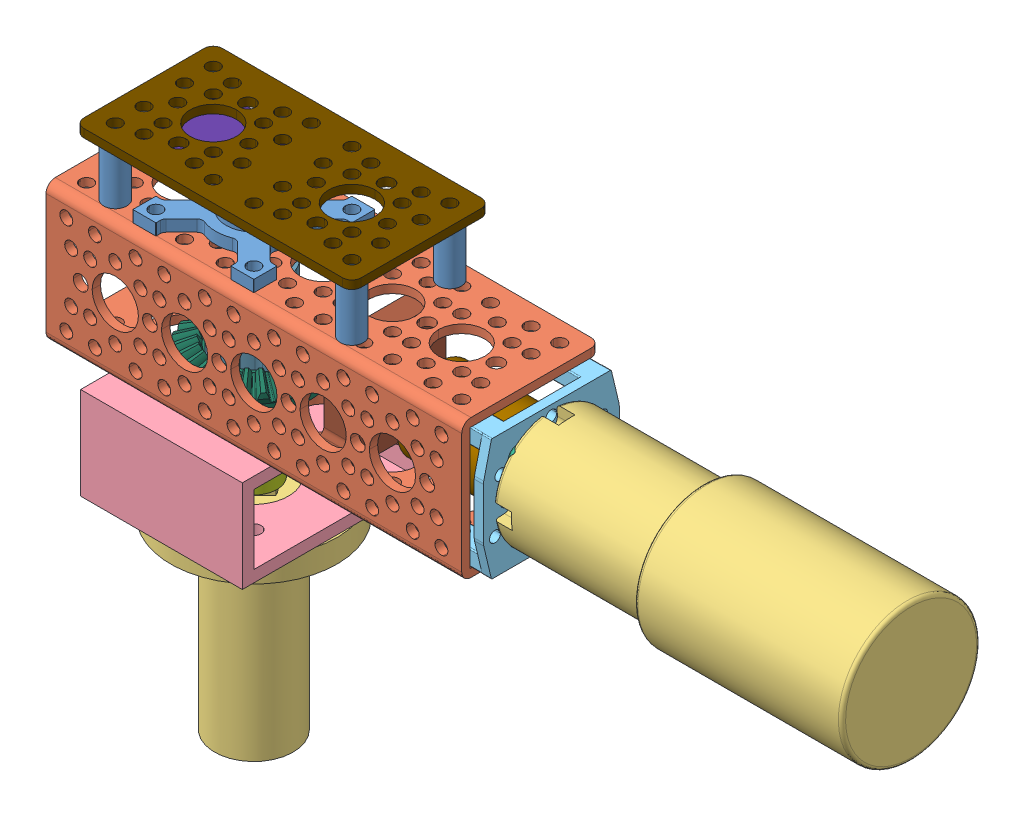
SolidWorks assembly LOX Valve, configuration Default. Lengths in mm.
Overall size (226.04 159.27 90.41).
38 component instances, 22 part files, 46 mates.
Components (placement in the parent):
- 535110 assembly - Pillow-1: 535110 assembly - Pillow [Default] at (31.7683 60.9694 -25.573) x (-0.000062 0 1) z (-1 0 -0.000062) size (33.27 5.08 33.27)
  - 535110 assembly - Pillow.STEP-1: 535110 assembly - Pillow.STEP [Default] at origin size (33.27 5.08 33.27)
    - 535110.STEP-1: 535110.STEP [Default] at (6.6273 15.2478 28.3097) size (33.27 5.08 33.27)
    - 535020.STEP-1: 535020.STEP [Default] at (6.6273 17.9338 28.3097) size (12.7 4.76 12.7)
- Motor_12VDC_638263-1: Motor_12VDC_638263 [Default] at (82.2478 57.1672 -18.9431) x (0 -0.998953 -0.04574) z (0 0.04574 -0.998953) size (38 101.9 38)
- Motor_12VDC_638263_shaft-1: Motor_12VDC_638263_shaft [Default] at (82.2478 57.1672 -18.9431) x (0 -0.998953 -0.04574) z (0 0.04574 -0.998953) size (6 16.2 6)
- 555188 assembly.STEP-1: 555188 assembly.STEP [Default] at (87.0217 63.6465 -16.3279) x (0 1 0) z (0 0 1) size (33.4 16.56 37.36)
  - 555188.STEP-1: 555188.STEP [Default] at (-6.4793 1.7739 -2.6152) size (33.4 14.22 37.36)
  - 555188 screw_92005A116.STEP-1: 555188 screw_92005A116.STEP [Default] at (-15.6717 7.7739 6.5772) x (1 0 0) z (0 -1 0) size (6 6 8.35)
  - 555188 screw_92005A116.STEP-2: 555188 screw_92005A116.STEP [Default] at (2.7131 7.7739 6.5772) x (0 0 -1) z (0 -1 0) size (6 6 8.35)
  - 555188 screw_92005A116.STEP-3: 555188 screw_92005A116.STEP [Default] at (2.7131 7.7739 -11.8076) x (-1 0 0) z (0 -1 0) size (6 6 8.35)
  - 555188 screw_92005A116.STEP-4: 555188 screw_92005A116.STEP [Default] at (-15.6717 7.7739 -11.8076) x (0 0 1) z (0 -1 0) size (6 6 8.35)
- 625182 assembly-2: 625182 assembly [Default] at (-84.2332 5.7417 -25.2481) x (-0.912422 0 -0.40925) z (0.40925 0 -0.912422) size (12.69 19.05 12.7)
- D-shaft-2.25in-1: D-shaft-2.25in [Default] at (3.4582 25.9129 -18.9475) x (0.746779 0 -0.665072) z (0.665072 0 0.746779) size (6.35 57.15 7.62)
- 625100 assembly.STEP-1: 625100 assembly.STEP [Default] at (87.2312 83.6106 5.6212) x (0 0.726073 0.687617) z (-1 0 0) size (50.01 22.2 75.17)
  - 625100.STEP-1: 625100.STEP [Default] at (-36.0907 -0.3474 4.9835) size (22.23 22.2 28.57)
  - 632112_90128A121.STEP-1: 632112_90128A121.STEP [Default] at (-1.3244 -7.8756 30.0025) x (0 0 -1) z (1 0 0) size (5.61 5.61 14.62)
  - 632112_90128A121.STEP-2: 632112_90128A121.STEP [Default] at (-1.3244 -7.8756 23.5255) x (0 0 -1) z (1 0 0) size (5.61 5.61 14.62)
  - 632112_90128A121.STEP-3: 632112_90128A121.STEP [Default] at (-1.3244 -7.8756 15.0165) x (0 0 -1) z (1 0 0) size (5.61 5.61 14.62)
  - 632112_90128A121.STEP-4: 632112_90128A121.STEP [Default] at (-1.3244 -7.8756 8.5395) x (0 0 -1) z (1 0 0) size (5.61 5.61 14.62)
- 535130 assembly.STEP-1: 535130 assembly.STEP [Default] at (22.1195 49.5488 9.4486) x (0 1 0) z (0 0 -1) size (33.54 6.36 33.02)
  - 535130.STEP-1: 535130.STEP [Default] at (7.6184 14.2154 28.3917) size (33.54 6.36 33.02)
  - 535020.STEP-1: 535020.STEP [Default] at (7.6184 18.1715 28.3917) size (12.7 4.76 12.7)
- 615458 assembly.STEP-1: 615458 assembly.STEP [Default] at (-39.0871 82.1155 -34.6634) x (-1 0 0) z (0 -0.723056 0.690789) size (72.51 19.24 80.12)
  - 615458.STEP-1: 615458.STEP [Default] at (-61.4441 5.8673 28.8984) size (15.1 19.24 19.22)
  - 632110_90128A121.STEP-1: 632110_90128A121.STEP [Default] at (-66.148 1.368 -6.0266) x (-0.354662 -0.934995 0) z (0 0 -1) size (5.61 5.61 13.03)
- 545309.step-1: 545309.step [Default] at (3.4582 53.843 -18.9475) x (0.920966 0 -0.389644) z (0 -1 0) size (17.78 17.76 20.07)
- 615460.step-1: 615460.step [Default] at (3.4582 43.8848 -18.9475) x (0 1 0) z (-0.857986 0 0.513673) size (8.04 33.75 33.87)
- D-shaft-2in-3: D-shaft-2in [Default] at (16.4618 57.1672 -18.9431) x (0 -0.983443 -0.181218) z (0 -0.181218 0.983443) size (5.71 50.8 6.35)
- AS5047 eval board-1: AS5047 eval board [Default] at (-3.2261 90.8222 -18.8412) x (1 0 0.000062) z (-0.000062 0 1) size (28 1.27 22)
- 585422.step-1: 585422.step [Default] at (11.3489 92.0922 -18.947) x (1 0 0.000062) z (-0.000062 0 1) size (76.2 2.29 38.1)
- .625in standoff-1: .625in standoff [Default] at (43.8685 92.0922 -5.4746) x (-0.12043 0 -0.992722) z (-0.992722 0 0.12043) size (6.35 15.88 6.35)
- .625in standoff-2: .625in standoff [Default] at (43.8701 76.2172 -32.4154) x (0.998481 0 -0.055099) z (0.055099 0 0.998481) size (6.35 15.88 6.35)
- 585444-2: 585444 [Default] at (-34.643 76.2172 0.1002) x (0 -1 0) z (1 0 0.000062) size (38.1 38.1 114.3)
- LOX Valve Body-1: LOX Valve Body [Default] at (3.4582 6.3672 -18.9475) x (-0.707063 0 -0.70715) z (0.70715 0 -0.707063) size (45.72 66.04 45.72)
- Lox-bracket-2-2: Lox-bracket-2 [Default] at (3.4582 12.7172 -18.9475) x (-0.000062 0 1) z (-1 0 -0.000062) size (50.8 25.4 44.45)
- .625in standoff-3: .625in standoff [Default] at (-21.1706 92.0922 -32.4194) x (-0.12043 0 -0.992722) z (-0.992722 0 0.12043) size (6.35 15.88 6.35)
- .625in standoff-4: .625in standoff [Default] at (-21.1723 92.0922 -5.4786) x (-0.119905 0 -0.992785) z (-0.992785 0 0.119905) size (6.35 15.88 6.35)
Mates (geometry in assembly coordinates):
- Concentric8: concentric: circle of Motor_12VDC_638263-1; circle of Motor_12VDC_638263_shaft-1
- Coincident8: coincident: plane of Motor_12VDC_638263-1 through (82.2478 57.1672 -18.9431) normal (-1 0 0); plane of Motor_12VDC_638263_shaft-1 through (82.2478 57.1672 -18.9431) normal (1 0 0)
- Concentric10: concentric: cylinder of Motor_12VDC_638263-1 through (127.0478 57.1672 -18.9431) axis (-1 0 0) radius 16; circle of 555188 assembly.STEP-1/555188.STEP-1
- Distance4: distance = 2.54 mm: plane of Motor_12VDC_638263-1 through (85.2478 57.1672 -18.9431) normal (-1 0 0); plane of 555188 assembly.STEP-1/555188.STEP-1 through (82.7078 57.1672 -18.9431) normal (-1 0 0)
- Coincident16: coincident: circle of 625182 assembly-2; plane of D-shaft-2.25in-1 through (3.4582 25.9129 -18.9475) normal (0 -1 0)
- Concentric13: concentric: cylinder of 625182 assembly-2 through (3.4582 34.9422 -18.9475) axis (0 1 0) radius 3.175; cylinder of D-shaft-2.25in-1 through (3.4582 83.0629 -18.9475) axis (0 -1 0) radius 3.175
- Concentric20: concentric: cylinder of Motor_12VDC_638263_shaft-1 through (66.0478 57.1672 -18.9431) axis (1 0 0) radius 3; cylinder of 625100 assembly.STEP-1/625100.STEP-1 through (67.9603 57.1672 -18.9431) axis (-1 0 0) radius 3
- Coincident25: coincident: plane of Motor_12VDC_638263-1 through (82.2478 57.1672 -18.9431) normal (-1 0 0); plane of 625100 assembly.STEP-1/625100.STEP-1 through (82.2478 57.1672 -18.9431) normal (1 0 0)
- Concentric21: concentric: cylinder of D-shaft-2.25in-1 through (3.4582 83.0629 -18.9475) axis (0 -1 0) radius 3.175; cylinder of 545309.step-1 through (3.4582 47.493 -18.9475) axis (0 1 0) radius 3.175
- Coincident26: coincident: cylinder of D-shaft-2.25in-1 through (3.4582 83.0629 -18.9475) axis (0 -1 0) radius 3.175; circle of 615460.step-1
- Coincident28: coincident: plane of 545309.step-1 through (3.4582 47.493 -18.9475) normal (0 -1 0); plane of 615460.step-1 through (3.4582 47.493 -18.9475) normal (0 1 0)
- Concentric22: concentric: cylinder of 625100 assembly.STEP-1/625100.STEP-1 through (67.9603 57.1672 -18.9431) axis (-1 0 0) radius 3; cylinder of 615458 assembly.STEP-1/615458.STEP-1 through (15.484 57.1672 -18.9431) axis (1 0 0) radius 3
- Concentric32: concentric: cylinder of 625100 assembly.STEP-1/625100.STEP-1 through (67.9603 57.1672 -18.9431) axis (-1 0 0) radius 3; cylinder of D-shaft-2in-3 through (67.2618 57.1672 -18.9431) axis (-1 0 0) radius 3.175
- Coincident36: coincident: plane of 625100 assembly.STEP-1/625100.STEP-1 through (67.2618 41.4771 -18.5364) normal (1 0 0); plane of D-shaft-2in-3 through (67.2618 57.1672 -18.9431) normal (1 0 0)
- Coincident43: coincident: plane of 585422.step-1 through (11.3489 92.0922 -18.947) normal (0 -1 0); plane of .625in standoff-2 through (43.8701 92.0922 -32.4154) normal (0 1 0)
- Concentric38: concentric: circle of 585422.step-1; cylinder of .625in standoff-2 through (43.8701 92.0922 -32.4154) axis (0 -1 0) radius 3.175
- Concentric39: concentric: cylinder of .625in standoff-1 through (43.8685 76.2172 -5.4746) axis (0 1 0) radius 3.175; cylinder of 585422.step-1 through (43.8685 94.3782 -5.4746) axis (0 1 0) radius 1.778
- Coincident44: coincident: plane of 585422.step-1 through (11.3489 92.0922 -18.947) normal (0 -1 0); plane of .625in standoff-1 through (43.8685 92.0922 -5.4746) normal (0 1 0)
- Coincident45: coincident: plane of AS5047 eval board-1 through (-3.2261 92.0922 -18.8412) normal (0 1 0); plane of 585422.step-1 through (11.3489 92.0922 -18.947) normal (0 -1 0)
- Parallel4: parallel: line of AS5047 eval board-1 through (-17.2268 92.0922 -7.842) axis (1 0 0.000062); plane of 585422.step-1 through (-26.7523 94.3782 0.1007) normal (-0.000062 0 1)
- Distance6: distance = 8.255 mm: line of AS5047 eval board-1 through (10.7746 90.8222 -29.8403) axis (-1 0 -0.000062); line of 585422.step-1 through (46.9101 92.0922 -37.9948) axis (-1 0 -0.000062)
- Coincident47: coincident: plane of D-shaft-2in-3 through (16.4618 57.1672 -18.9431) normal (-1 0 0); plane of 615458 assembly.STEP-1/615458.STEP-1 through (16.4618 57.1672 -18.9431) normal (-1 0 0)
- Distance8: distance = 9.525 mm: plane of 585422.step-1 through (-26.7523 94.3782 0.1007) normal (-1 0 -0.000062); plane of AS5047 eval board-1 through (-17.2254 92.0922 -29.842) normal (-1 0 -0.000062)
- Concentric44: concentric: circle of 535110 assembly - Pillow-1/535110 assembly - Pillow.STEP-1/535110.STEP-1; cylinder of D-shaft-2.25in-1 through (3.4582 83.0629 -18.9475) axis (0 -1 0) radius 3.175
- Concentric47: concentric: cylinder of 625182 assembly-2 through (3.4582 34.9422 -18.9475) axis (0 -1 0) radius 6.3462; circle of LOX Valve Body-1
- Concentric50: concentric: cylinder of D-shaft-2.25in-1 through (3.4582 83.0629 -18.9475) axis (0 -1 0) radius 3.175; cylinder of 585444-2 through (3.4582 38.1172 -18.9475) axis (0 -1 0) radius 6.3627
- Concentric53: concentric: cylinder of LOX Valve Body-1 through (3.4582 12.7172 -18.9475) axis (0 -1 0) radius 22.86; cylinder of Lox-bracket-2-2 through (3.4582 12.7172 -18.9475) axis (0 1 0) radius 9.525
- Coincident55: coincident: cylinder of LOX Valve Body-1 through (16.1869 12.7172 -31.6746) axis (0 1 0) radius 1.9844; circle of Lox-bracket-2-2
- Coincident56: coincident: plane of LOX Valve Body-1 through (3.4582 12.7172 -18.9475) normal (0 1 0); plane of Lox-bracket-2-2 through (-18.7653 12.7172 -44.3488) normal (0 -1 0)
- Distance9: distance = 1.27 mm: plane of 615460.step-1 through (3.4582 41.6732 -18.9475) normal (0 -1 0); plane of 585444-2 through (79.6571 40.4032 -2.1788) normal (0 1 0)
- Coincident58: coincident: plane of 585444-2 through (79.6593 38.1172 -37.9928) normal (0 -1 0); plane of Lox-bracket-2-2 through (-18.7653 38.1172 -44.3488) normal (0 1 0)
- Tangent1: tangent: curve of 535130 assembly.STEP-1/535130.STEP-1; cylinder of 585444-2 through (35.9794 38.1172 -32.4158) axis (0 -1 0) radius 1.778
- Coincident60: coincident: plane of 535130 assembly.STEP-1/535130.STEP-1 through (42.685 73.9312 -35.4531) normal (0 1 0); plane of 585444-2 through (79.6593 73.9312 -37.9928) normal (0 -1 0)
- Concentric54: concentric: cylinder of 535130 assembly.STEP-1/535020.STEP-1 through (42.6723 57.1672 -18.9431) axis (-1 0 0) radius 3.175; cylinder of D-shaft-2in-3 through (67.2618 57.1672 -18.9431) axis (-1 0 0) radius 3.175
- Concentric55: concentric: circle of 555188 assembly.STEP-1/555188.STEP-1; cylinder of 585444-2 through (74.0794 38.1172 -32.4135) axis (0 -1 0) radius 1.778
- Coincident61: coincident: plane of 625182 assembly-2 through (3.4582 15.8922 -18.9475) normal (0 -1 0); plane of Lox-bracket-2-2 through (-18.7655 15.8922 -41.1738) normal (0 1 0)
- Coincident62: coincident: plane of 585444-2 through (79.6593 40.4032 -37.9928) normal (0.000062 0 -1); plane of Lox-bracket-2-2 through (-18.7653 38.1172 -44.3488) normal (0.000062 0 -1)
- Parallel5: parallel: plane of 535110 assembly - Pillow-1/535110 assembly - Pillow.STEP-1/535110.STEP-1 through (3.4592 79.3922 -35.5845) normal (0.000062 0 -1); plane of 585444-2 through (79.6593 76.2172 -37.9928) normal (0.000062 0 -1)
- Coincident64: coincident: plane of 535110 assembly - Pillow-1/535110 assembly - Pillow.STEP-1/535110.STEP-1 through (3.4582 76.2172 -18.9475) normal (0 -1 0); plane of 585444-2 through (79.657 76.2172 0.1072) normal (0 1 0)
- Concentric58: concentric: cylinder of 585422.step-1 through (-21.1723 94.3782 -5.4786) axis (0 1 0) radius 1.778; cylinder of .625in standoff-4 through (-21.1723 76.2172 -5.4786) axis (0 1 0) radius 3.175
- Coincident65: coincident: plane of 585422.step-1 through (11.3489 92.0922 -18.947) normal (0 -1 0); plane of .625in standoff-4 through (-21.1723 92.0922 -5.4786) normal (0 1 0)
- Concentric59: concentric: cylinder of 585422.step-1 through (-21.1706 94.3782 -32.4194) axis (0 1 0) radius 1.778; cylinder of .625in standoff-3 through (-21.1706 76.2172 -32.4194) axis (0 1 0) radius 3.175
- Coincident66: coincident: plane of 585422.step-1 through (11.3489 92.0922 -18.947) normal (0 -1 0); plane of .625in standoff-3 through (-21.1706 92.0922 -32.4194) normal (0 1 0)
- Concentric60: concentric: cylinder of 585444-2 through (-21.1723 38.1172 -5.4786) axis (0 -1 0) radius 1.778; cylinder of .625in standoff-4 through (-21.1723 76.2172 -5.4786) axis (0 1 0) radius 3.175
- Parallel6: parallel: plane of 585422.step-1 through (-26.7499 94.3782 -37.9993) normal (0.000062 0 -1); line of 585444-2 through (77.1193 76.2172 -37.9929) axis (-1 0 -0.000062)
- Coincident68: coincident: plane of .625in standoff-1 through (43.8685 76.2172 -5.4746) normal (0 -1 0); plane of 585444-2 through (79.657 76.2172 0.1072) normal (0 1 0)
